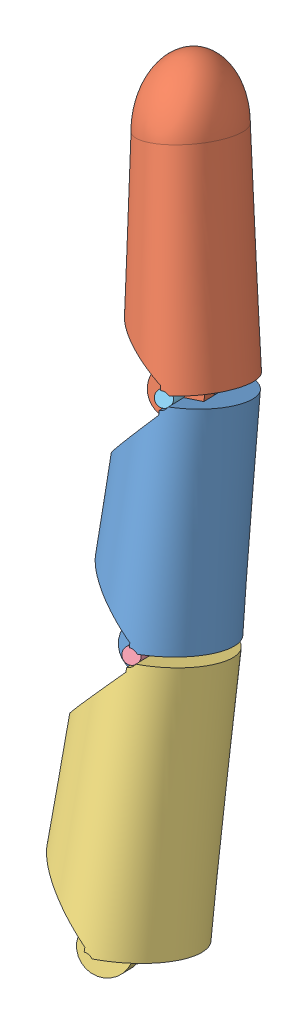
SolidWorks assembly finger, configuration Default. Lengths in mm.
Overall size (39.48 95 52.05).
5 component instances, 5 part files, 8 mates.
Components (placement in the parent):
- part12-1: part12 [Default] at (-1.7536 63.4783 2.9462) x (-0.37395 -0.360461 -0.854534) z (-0.912407 -0.022287 0.408677) size (20.07 32 15.01)
- part13-1: part13 [Default] at (-8.8406 87.4834 -4.0784) x (-0.37395 -0.360461 -0.854534) z (-0.885847 -0.134042 0.444194) size (18.07 36.5 13.01)
- part 11-2: part 11 [Default] at (2.5604 39.2329 11.2856) x (-0.37395 -0.360461 -0.854534) z (-0.916242 0.000782 0.400624) size (22.08 37 17.01)
- mate1-1: mate1 [Default] at (-0.877 36.4552 3.4295) x (-0.919414 0.265096 0.290519) z (0.37395 0.360461 0.854534) size (2 2 18)
- mate2-1: mate2 [Default] at (-4.8284 61.0608 -4.0504) x (-0.079899 -0.905435 0.416897) z (0.37395 0.360461 0.854534) size (2 2 16)
Mates (geometry in assembly coordinates):
- Concentric1: concentric aligned: cylinder of part12-1 through (6.232 43.3078 19.6747) axis (-0.37395 -0.360461 -0.854534) radius 1; cylinder of part 11-2 through (6.6062 43.6684 20.5298) axis (-0.37395 -0.360461 -0.854534) radius 1
- Coincident1: coincident anti-aligned: plane of part12-1 through (3.0494 40.24 12.4021) normal (-0.37395 -0.360461 -0.854534); plane of part 11-2 through (3.0494 40.24 12.4021) normal (0.37395 0.360461 0.854534)
- Concentric2: concentric anti-aligned: cylinder of part12-1 through (1.1036 67.5193 11.706) axis (-0.37395 -0.360461 -0.854534) radius 1; cylinder of part13-1 through (-6.009 60.6633 -4.5474) axis (0.37395 0.360461 0.854534) radius 1
- Coincident2: coincident anti-aligned: plane of part12-1 through (-2.0789 64.4516 4.4333) normal (0.37395 0.360461 0.854534); plane of part13-1 through (-2.0789 64.4516 4.4333) normal (-0.37395 -0.360461 -0.854534)
- Concentric3: concentric aligned: cylinder of part12-1 through (6.232 43.3078 19.6747) axis (-0.37395 -0.360461 -0.854534) radius 1; cylinder of mate1-1 through (5.8541 42.9435 18.8111) axis (-0.37395 -0.360461 -0.854534) radius 1
- Width1: width anti-aligned: plane of mate1-1 through (5.8541 42.9435 18.8111) normal (0.37395 0.360461 0.854534); plane of part12-1 through (-0.877 36.4552 3.4295) normal (-0.37395 -0.360461 -0.854534); plane of mate1-1 through (0.8057 38.0772 7.2749) normal (-0.37395 -0.360461 -0.854534); plane of part12-1 through (4.1713 41.3214 14.9657) normal (0.37395 0.360461 0.854534)
- Concentric4: concentric anti-aligned: cylinder of part13-1 through (-6.009 60.6633 -4.5474) axis (0.37395 0.360461 0.854534) radius 1; cylinder of mate2-1 through (0.3517 66.7946 9.9878) axis (-0.37395 -0.360461 -0.854534) radius 1
- Width2: width anti-aligned: plane of mate2-1 through (0.3517 66.7946 9.9878) normal (0.37395 0.360461 0.854534); plane of part13-1 through (-5.6315 61.0272 -3.6847) normal (-0.37395 -0.360461 -0.854534); plane of mate2-1 through (-4.3226 62.2888 -0.6939) normal (-0.37395 -0.360461 -0.854534); plane of part13-1 through (-0.9571 65.5329 6.9969) normal (0.37395 0.360461 0.854534)
